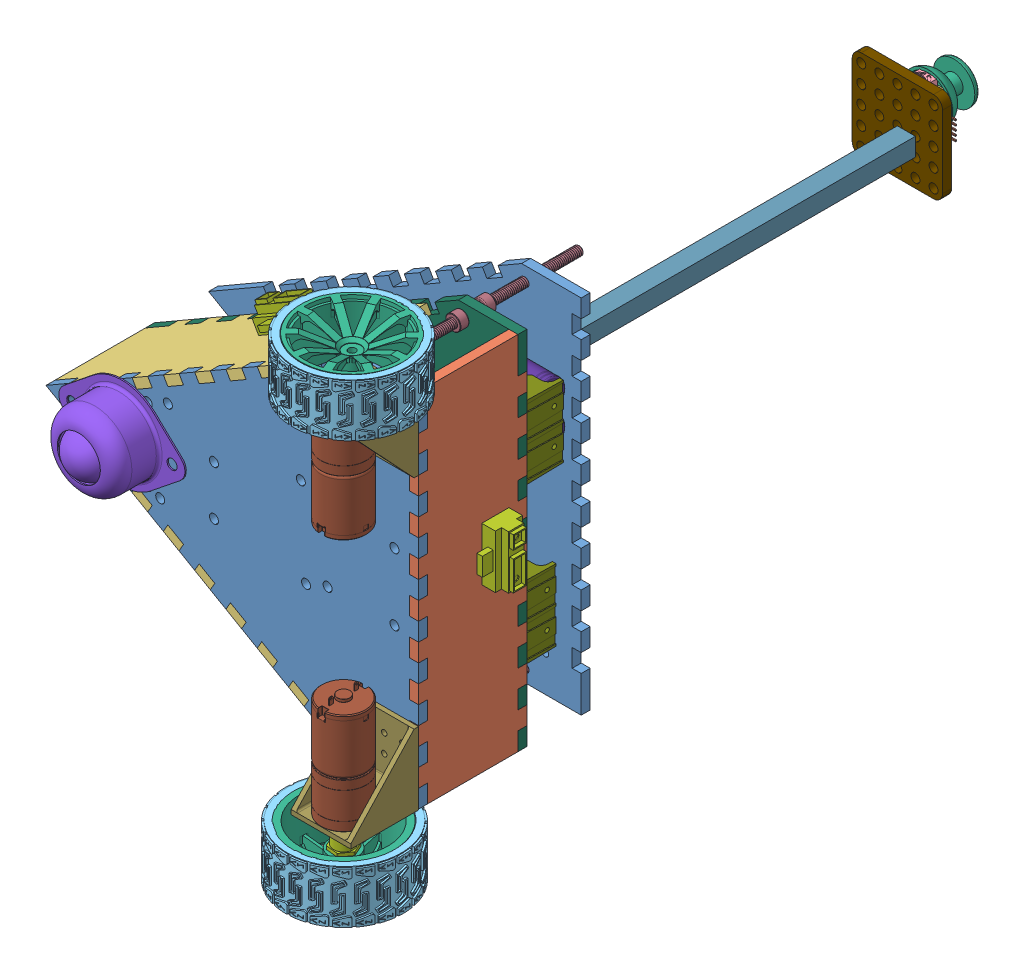
SolidWorks assembly Final_R03, configuration Default. Lengths in mm.
Overall size (224.4 260.03 452.74).
45 component instances, 25 part files, 65 mates.
Components (placement in the parent):
- triangular base 1-1: triangular base 1 [Default] at (154.8111 203.7551 170.4098) size (206.21 200 5)
- the back wall-1: the back wall [Default] at (152.3111 203.7551 170.4098) x (1 0 0) z (0 1 0) size (5 60 200)
- Walls-1: Walls [Default] at (-31.5732 93.7549 170.4098) x (0.866025 -0.5 0) z (0.5 0.866025 0) size (180 60 5)
- Walls-2: Walls [Default] at (-46.394 99.4249 170.4098) x (0.866025 0.5 0) z (-0.5 0.866025 0) size (180 60 5)
- ArduinoMega2560-1: ArduinoMega2560 [Predeterminado] at (124.9198 138.7551 169.4098) x (0 1 0) z (-1 0 0) size (100 11.65 51.63)
- blue_wheel_with_adapter-1: blue_wheel_with_adapter [Default] at (122.4376 180.4937 248.1171) x (1 0 0) z (0 1 0) size (69.31 69.31 29.8)
  - 65mm tire-1: 65mm tire [Default] at (18.1044 52.2783 38.5614) x (-0.068419 0.997657 0) z (0 0 1) size (65.01 65.01 29)
  - blue_wheel_frame-2: blue_wheel_frame [Default] at (18.0756 52.6985 38.5614) x (0 0 -1) z (-0.994893 -0.10093 0) size (29 56 56)
  - motor_adapter-1: motor_adapter [Default] at (18.0661 52.7117 35.2614) x (0.583313 -0.812247 0) z (0 0 1) size (13.7 12 18.23)
- blue_wheel_with_adapter-2: blue_wheel_with_adapter [Default] at (122.7449 26.5815 147.6981) x (1 0 0) z (0 -1 0) size (69.31 69.31 29.8)
  - 65mm tire-1: 65mm tire [Default] at (18.1044 52.2783 38.5614) x (-0.068419 0.997657 0) z (0 0 1) size (65.01 65.01 29)
  - blue_wheel_frame-2: blue_wheel_frame [Default] at (18.0756 52.6985 38.5614) x (0 0 -1) z (-0.994893 -0.10093 0) size (29 56 56)
  - motor_adapter-1: motor_adapter [Default] at (18.0661 52.7117 35.2614) x (0.583313 -0.812247 0) z (0 0 1) size (13.7 12 18.23)
- Flange-Mount Ball Transfer-1: Flange-Mount Ball Transfer [Default] at (-6.1349 102.6468 176.1718) x (0.039893 0.999204 0) z (-0.999204 0.039893 0) size (50.8 30.16 69.85)
- l298n1-1: l298n1 [Default] at (23.2111 102.2551 170.4098) x (0 -1 0) z (0 0 -1) size (43 43 26.5)
- MiniBreadboard-1: MiniBreadboard [Default] at (129.5111 61.4551 170.4098) x (0 1 0) z (-1 0 0) size (34.6 8.15 45.6)
- JGA25-372 24V Motor-1: JGA25-372 24V Motor [Ratio 171 & 226] at (140.8111 5.8202 200.4098) x (0 0 -1) z (-1 0 0) size (25.02 71.1 25)
- JGA25-372 24V Motor-2: JGA25-372 24V Motor [Ratio 171 & 226] at (140.8111 201.2551 200.4098) x (0 0 1) z (-1 0 0) size (25.02 71.1 25)
- L HOLDER DC MOTOR-1: L HOLDER DC MOTOR [Default] at (126.8111 203.7551 175.4098) x (1 0 0) z (0 -1 0) size (33 37.5 40)
- L HOLDER DC MOTOR-2: L HOLDER DC MOTOR [Default] at (154.8111 3.3202 175.4098) x (-1 0 0) z (0 1 0) size (33 37.5 40)
- M5 x 50mm CAPHEAD BOLT-1: M5 x 50mm CAPHEAD BOLT [Default] at (126.3207 196.2551 125.4098) x (1 0 0) z (0 1 0) size (8.4 55.33 8.4)
- M5 x 50mm CAPHEAD BOLT-2: M5 x 50mm CAPHEAD BOLT [Default] at (126.3207 11.2551 125.4098) x (0.989821 -0.142315 0) z (0.142315 0.989821 0) size (8.4 55.33 8.4)
- IV Stand-1: IV Stand [Default] at (72.3111 103.7551 -179.5902) x (1 0 0) z (0 -1 0) size (10 350 10)
- 1st Layer-1: 1st Layer [Default] at (154.8111 203.7551 115.4098) size (206.21 200 5)
- Batt_Pack_Main-1: Batt_Pack_Main [Défaut] at (154.2111 148.5592 115.4098) x (0 1 0) z (-1 0 0) size (40.4 21.36 77.92)
- Batt_Pack_Main-2: Batt_Pack_Main [Défaut] at (76.4911 58.5407 115.4102) x (0 -1 0) z (1 0 0) size (40.4 21.36 77.92)
- Batt_main-1: Batt_main [Défaut] at (84.3111 68.6601 104.2466) x (0 -1 0) z (0 0 1) size (18.2 64.88 18.2)
- Batt_main-2: Batt_main [Défaut] at (85.3311 157.6592 96.0342) x (0 -0.990599 -0.136795) z (0 -0.136795 0.990599) size (18.2 64.88 18.2)
- Batt_main-5: Batt_main [Défaut] at (85.3311 139.4592 96.0342) x (0 0.990599 -0.136795) z (0 -0.136795 -0.990599) size (18.2 64.88 18.2)
- Batt_main-6: Batt_main [Défaut] at (84.3111 48.4213 104.2466) x (0 1 0) z (0 0 -1) size (18.2 64.88 18.2)
- M5 x 50mm CAPHEAD BOLT-4: M5 x 50mm CAPHEAD BOLT [Default] at (126.3207 11.2551 105.4098) x (0.989821 -0.142315 0) z (-0.142315 -0.989821 0) size (8.4 55.33 8.4)
- M5 x 50mm CAPHEAD BOLT-5: M5 x 50mm CAPHEAD BOLT [Default] at (126.3207 196.2551 105.4098) x (1 0 0) z (0 -1 0) size (8.4 55.33 8.4)
- Addational useful layer 2-1: Addational useful layer 2 [Default] at (67.3111 108.7551 -179.5902) x (1 0 0) z (0 1 0) size (50 5 50)
- Top layer-1: Top layer [Default] at (154.8111 3.7551 85.4098) x (1 0 0) z (0 0 -1) size (206.21 200 5)
- Joystick assembly-1: Joystick assembly [Default] at (82.3111 123.7551 -186.0902) x (0 -1 0) z (1 0 0) size (30.12 34.52 39.55)
  - board-1: board [Default] at origin size (26.4 6.02 39.55)
  - Thumb Joystick-1: Thumb Joystick [기본] at (15.2543 37 -18.0537) x (1 0 0) z (0 -1 0) size (30.12 30.12 34.52)
    - body-1: body [기본] at (-10.9543 -7.0963 23.5) size (22.1 16 23.5)
    - potentiometer-1: potentiometer [기본] at (-2.9543 -7.0963 29) x (-1 0 0) z (0 -1 0) size (9.5 14.5 3.5)
    - potentiometer-2: potentiometer [기본] at (-10.9543 0.9037 29.5) x (0 1 0) z (-1 0 0) size (9.5 14.5 3.5)
    - tactileswitch-short-1: tactileswitch-short [Default] at (7.6493 0.9037 34) x (0 -1 0) z (1 0 0) size (6.89 8.33 6.01)
    - joystickhead-1: joystickhead [기본] at (-21.7711 -52.5336 38.75) x (0.118335 0.992974 0) z (0 0 -1) size (27.11 27.11 19.35)
- sharp 2y0a21 f 21-4: sharp 2y0a21 f 21 [Standard] at (157.3111 123.2551 140.4098) x (0 -1 0) z (0 0 1) size (29.5 13.5 21)
- sharp 2y0a21 f 21-5: sharp 2y0a21 f 21 [Standard] at (33.8114 151.5051 140.4098) x (0.866025 0.5 0) z (0 0 1) size (29.5 13.5 21)
- sharp 2y0a21 f 21-6: sharp 2y0a21 f 21 [Standard] at (59.6596 41.0816 140.4098) x (-0.866025 0.5 0) z (0 0 1) size (29.5 13.5 21)
Mates (geometry in assembly coordinates):
- Coincident3: coincident anti-aligned: plane of triangular base 1-1 through (154.8111 203.7551 175.4098) normal (0 0 1); plane of L HOLDER DC MOTOR-2 through (126.8111 43.3202 175.4098) normal (0 0 -1)
- Coincident5: coincident anti-aligned: plane of triangular base 1-1 through (154.8111 203.7551 175.4098) normal (0 0 1); plane of L HOLDER DC MOTOR-1 through (154.8111 163.7551 175.4098) normal (0 0 -1)
- Concentric6: concentric aligned: cylinder of JGA25-372 24V Motor-2 through (149.3111 201.2551 200.4098) axis (0 1 0) radius 1.25; cylinder of L HOLDER DC MOTOR-1 through (149.3111 163.7551 200.4098) axis (0 1 0) radius 1.5
- Concentric7: concentric anti-aligned: cylinder of JGA25-372 24V Motor-2 through (140.8111 218.4119 200.4098) axis (0 -1 0) radius 2; cylinder of L HOLDER DC MOTOR-1 through (140.8111 163.7551 200.4098) axis (0 1 0) radius 3.75
- Coincident7: coincident anti-aligned: plane of JGA25-372 24V Motor-1 through (140.8111 5.8202 200.4098) normal (0 -1 0); plane of L HOLDER DC MOTOR-2 through (126.8111 5.8202 212.9098) normal (0 1 0)
- Concentric8: concentric aligned: cylinder of JGA25-372 24V Motor-1 through (149.3111 5.8202 200.4098) axis (0 -1 0) radius 1.25; cylinder of L HOLDER DC MOTOR-2 through (149.3111 43.3202 200.4098) axis (0 -1 0) radius 1.5
- Concentric9: concentric aligned: cylinder of JGA25-372 24V Motor-1 through (132.3111 5.8202 200.4098) axis (0 -1 0) radius 1.25; cylinder of L HOLDER DC MOTOR-2 through (132.3111 43.3202 200.4098) axis (0 -1 0) radius 1.5
- Concentric13: concentric aligned: cylinder of triangular base 1-1 through (-33.894 103.7551 170.4098) axis (0 0 1) radius 2.5; cylinder of Flange-Mount Ball Transfer-1 through (-33.894 103.7551 175.4098) axis (0 0 1) radius 2.7781
- Coincident11: coincident anti-aligned: plane of triangular base 1-1 through (154.8111 203.7551 175.4098) normal (0 0 1); plane of Flange-Mount Ball Transfer-1 through (-6.1349 102.6468 175.4098) normal (0 0 -1)
- Coincident13: coincident aligned: line of triangular base 1-1 through (-48.894 103.7551 170.4098) axis (0.866025 0.5 0); line of Walls-2 through (-48.894 103.7551 170.4098) axis (0.866025 0.5 0)
- Coincident14: coincident aligned: line of triangular base 1-1 through (-48.894 103.7551 175.4098) axis (0 0 -1); line of Walls-2 through (-48.894 103.7551 170.4098) axis (0 0 -1)
- Coincident19: coincident aligned: line of triangular base 1-1 through (157.3111 203.7551 170.4098) axis (-1 0 0); line of the back wall-1 through (157.3111 203.7551 170.4098) axis (-1 0 0)
- Coincident20: coincident: moEndPointRef_w of triangular base 1-1; line of the back wall-1 through (157.3111 203.7551 120.4098) axis (0 0 1)
- Coincident26: coincident anti-aligned: plane of the back wall-1 through (152.3111 203.7551 170.4098) normal (-1 0 0); plane of MiniBreadboard-1 through (152.3111 44.1551 162.2598) normal (1 0 0)
- Coincident27: coincident aligned: plane of triangular base 1-1 through (154.8111 203.7551 175.4098) normal (0 1 0); plane of L HOLDER DC MOTOR-1 through (154.8111 203.7551 175.4098) normal (0 1 0)
- Concentric16: concentric anti-aligned: cylinder of blue_wheel_with_adapter-2/motor_adapter-1 through (140.8111 3.3202 200.4098) axis (0 -1 0) radius 5.5; cylinder of JGA25-372 24V Motor-1 through (140.8111 -11.3367 200.4098) axis (0 1 0) radius 2
- Coincident30: coincident anti-aligned: plane of blue_wheel_with_adapter-2/motor_adapter-1 through (140.8111 3.3202 200.4098) normal (0 1 0); plane of L HOLDER DC MOTOR-2 through (126.8111 3.3202 175.4098) normal (0 -1 0)
- Distance19: distance = 2 mm aligned: plane of ArduinoMega2560-1 through (124.9198 138.7551 168.4098) normal (0 0 -1); plane of triangular base 1-1 through (154.8111 203.7551 170.4098) normal (0 0 -1)
- Distance20: distance = 15 mm aligned: plane of ArduinoMega2560-1 through (98.4198 188.7551 168.4098) normal (0 1 0); plane of triangular base 1-1 through (154.8111 203.7551 175.4098) normal (0 1 0)
- Distance21: distance = 2 mm anti-aligned: plane of ArduinoMega2560-1 through (150.3111 188.7551 178.4098) normal (1 0 0); plane of the back wall-1 through (152.3111 203.7551 170.4098) normal (-1 0 0)
- Distance22: distance = 0 mm anti-aligned: plane of MiniBreadboard-1 through (106.7111 78.7551 170.4098) normal (0 0 1); plane of triangular base 1-1 through (154.8111 203.7551 170.4098) normal (0 0 -1)
- Distance23: distance = 10 mm anti-aligned: plane of MiniBreadboard-1 through (152.3111 78.7551 162.2598) normal (0 1 0); plane of ArduinoMega2560-1 through (98.4198 88.7551 168.4098) normal (0 -1 0)
- Coincident47: coincident aligned: plane of triangular base 1-1 through (154.8111 203.7551 170.4098) normal (0 0 -1); plane of l298n1-1 through (23.2111 102.2551 170.4098) normal (0 0 -1)
- Distance26: distance = 105 mm anti-aligned: plane of l298n1-1 through (1.7111 80.7551 170.4098) normal (1 0 0); plane of MiniBreadboard-1 through (106.7111 44.1551 162.2598) normal (-1 0 0)
- Distance27: distance = 80 mm anti-aligned: plane of triangular base 1-1 through (154.8111 203.7551 175.4098) normal (0 1 0); plane of l298n1-1 through (1.7111 123.7551 170.4098) normal (0 -1 0)
- Distance28: distance = 0 mm aligned: plane of Walls-1 through (-29.0732 98.085 175.4098) normal (0 0 1); plane of triangular base 1-1 through (154.8111 203.7551 175.4098) normal (0 0 1)
- Distance29: distance = -2000 mm anti-aligned: plane of triangular base 1-1 through (27.2181 65.5852 170.4098) normal (-0.5 -0.866025 0); plane of Walls-1 through (-29.0732 98.085 170.4098) normal (0.5 0.866025 0)
- Concentric18: concentric aligned: cylinder of triangular base 1-1 through (126.3207 196.2551 170.4098) axis (0 0 1) radius 2.5; cylinder of M5 x 50mm CAPHEAD BOLT-1 through (126.3207 196.2551 120.4098) axis (0 0 1) radius 4.2
- Coincident54: coincident aligned: plane of triangular base 1-1 through (157.3111 203.7551 175.4098) normal (1 0 0); plane of L HOLDER DC MOTOR-1 through (157.3111 203.7551 175.4098) normal (1 0 0)
- Distance36: distance = 0 mm: cylinder of blue_wheel_with_adapter-1/motor_adapter-1 through (140.5132 215.7551 195.4186) axis (0 -1 0) radius 3; cylinder of JGA25-372 24V Motor-2 through (140.8111 218.4119 200.4098) axis (0 -1 0) radius 2
- Distance37: distance = 0 mm anti-aligned: plane of blue_wheel_with_adapter-1/motor_adapter-1 through (140.5038 203.7551 195.4054) normal (0 -1 0); plane of L HOLDER DC MOTOR-1 through (154.8111 203.7551 175.4098) normal (0 1 0)
- Distance42: distance = 50 mm aligned: plane of M5 x 50mm CAPHEAD BOLT-2 through (126.3207 11.2551 120.4098) normal (0 0 -1); plane of triangular base 1-1 through (154.8111 203.7551 170.4098) normal (0 0 -1)
- Concentric23: concentric anti-aligned: circle of triangular base 1-1; circle of M5 x 50mm CAPHEAD BOLT-2
- Distance44: distance = 0 mm anti-aligned: plane of IV Stand-1 through (72.3111 103.7551 170.4098) normal (0 0 1); plane of triangular base 1-1 through (154.8111 203.7551 170.4098) normal (0 0 -1)
- Distance45: distance = 80 mm aligned: plane of IV Stand-1 through (77.3111 108.7551 170.4098) normal (1 0 0); plane of the back wall-1 through (157.3111 203.7551 170.4098) normal (1 0 0)
- Distance46: distance = 95 mm aligned: plane of IV Stand-1 through (67.3111 108.7551 170.4098) normal (0 1 0); plane of the back wall-1 through (157.3111 203.7551 170.4098) normal (0 1 0)
- Coincident71: coincident aligned: plane of the back wall-1 through (157.3111 203.7551 170.4098) normal (1 0 0); plane of 1st Layer-1 through (157.3111 203.7551 120.4098) normal (1 0 0)
- Distance56: distance = 0 mm aligned: plane of 1st Layer-1 through (154.8111 3.7551 120.4098) normal (0 -1 0); plane of triangular base 1-1 through (154.8111 3.7551 175.4098) normal (0 -1 0)
- Coincident74: coincident anti-aligned: plane of the back wall-1 through (157.3111 203.7551 120.4098) normal (0 0 -1); plane of 1st Layer-1 through (154.8111 203.7551 120.4098) normal (0 0 1)
- Distance62: distance = 1 mm aligned: plane of Batt_Pack_Main-1 through (156.3111 148.5592 115.4098) normal (1 0 0); plane of the back wall-1 through (157.3111 203.7551 170.4098) normal (1 0 0)
- Distance70: distance = 90 mm aligned: plane of Batt_Pack_Main-2 through (150.2111 78.7324 115.0009) normal (0 0.999795 -0.020266); plane of Batt_Pack_Main-1 through (80.4911 168.7509 115.0005) normal (0 0.999795 -0.020266)
- Distance71: distance = 5 mm aligned: plane of Batt_Pack_Main-2 through (152.3111 58.5407 115.4102) normal (1 0 0); plane of the back wall-1 through (157.3111 203.7551 170.4098) normal (1 0 0)
- Tangent3: tangent anti-aligned: plane of Batt_Pack_Main-1; cylinder of Batt_main-2 through (85.3311 157.6592 96.0342) axis (-1 0 0) radius 9.1
- Coincident95: coincident anti-aligned: plane of Batt_Pack_Main-1 through (150.2111 148.5592 98.6698) normal (-1 0 0); plane of Batt_main-2 through (150.2111 157.6592 96.0342) normal (1 0 0)
- Coincident96: coincident anti-aligned: plane of Batt_Pack_Main-1 through (84.4911 148.5592 98.6698) normal (1 0 0); plane of Batt_main-1 through (84.4911 61.6601 104.2466) normal (-1 0 0)
- Parallel19: parallel aligned: cylinder of Batt_main-1 through (84.3111 68.6601 104.2466) axis (-1 0 0) radius 9.1; cylinder of Batt_main-2 through (85.3311 157.6592 96.0342) axis (-1 0 0) radius 9.1
- Parallel21: parallel anti-aligned: plane of Batt_Pack_Main-2 through (146.2111 58.5407 98.6702) normal (-1 0 0); plane of Batt_main-1 through (149.1911 68.6601 104.2466) normal (1 0 0)
- Coincident97: coincident anti-aligned: plane of IV Stand-1 through (72.3111 103.7551 -179.5902) normal (0 0 -1); plane of Addational useful layer 2-1 through (87.3111 88.7551 -179.5902) normal (0 0 1)
- Distance73: distance = 25 mm aligned: plane of IV Stand-1 through (67.3111 108.7551 170.4098) normal (0 1 0); plane of Addational useful layer 2-1 through (87.3111 133.7551 -184.5902) normal (0 1 0)
- Distance72: distance = 25 mm aligned: plane of Addational useful layer 2-1 through (42.3111 128.7551 -184.5902) normal (-1 0 0); plane of IV Stand-1 through (67.3111 108.7551 170.4098) normal (-1 0 0)
- Coincident101: coincident aligned: plane of 1st Layer-1 through (154.8111 203.7551 120.4098) normal (0 1 0); plane of Top layer-1 through (154.8111 203.7551 80.4098) normal (0 1 0)
- Coincident103: coincident aligned: plane of the back wall-1 through (157.3111 203.7551 170.4098) normal (1 0 0); plane of Top layer-1 through (157.3111 3.7551 80.4098) normal (1 0 0)
- Distance74: distance = 35 mm aligned: plane of Top layer-1 through (154.8111 3.7551 80.4098) normal (0 0 -1); plane of 1st Layer-1 through (154.8111 203.7551 115.4098) normal (0 0 -1)
- Distance77: distance = 3 mm: plane of Addational useful layer 2-1 through (87.3111 88.7551 -184.5902) normal (0 0 -1); line of Joystick assembly-1/Thumb Joystick-1/body-1 through (73.1611 105.1551 -187.5902) axis (0 1 0)
- Distance82: distance = 10 mm aligned: plane of Addational useful layer 2-1 through (92.3111 128.7551 -184.5902) normal (1 0 0); plane of Joystick assembly-1/board-1 through (82.3111 123.7551 -187.5902) normal (1 0 0)
- Distance83: distance = 10 mm aligned: plane of Joystick assembly-1/board-1 through (82.3111 123.7551 -187.5902) normal (0 1 0); plane of Addational useful layer 2-1 through (87.3111 133.7551 -184.5902) normal (0 1 0)
- Coincident118: coincident anti-aligned: plane of Walls-2 through (-48.894 103.7551 170.4098) normal (-0.5 0.866025 0); plane of sharp 2y0a21 f 21-5 through (33.8114 151.5051 125.4098) normal (0.5 -0.866025 0)
- Distance84: distance = 55 mm aligned: plane of Walls-2 through (106.9905 193.7551 170.4098) normal (0.866025 0.5 0); plane of sharp 2y0a21 f 21-5 through (55.6091 172.7503 140.4098) normal (0.866025 0.5 0)
- Distance85: distance = 10 mm aligned: plane of 1st Layer-1 through (154.8111 203.7551 115.4098) normal (0 0 -1); plane of sharp 2y0a21 f 21-5 through (30.0614 158.0003 125.4098) normal (0 0 -1)
- Coincident121: coincident anti-aligned: plane of Walls-1 through (-31.5732 93.7549 170.4098) normal (-0.5 -0.866025 0); plane of sharp 2y0a21 f 21-6 through (59.6596 41.0816 125.4098) normal (0.5 0.866025 0)
- Distance88: distance = 10 mm aligned: plane of sharp 2y0a21 f 21-6 through (55.9096 34.5864 125.4098) normal (0 0 -1); plane of 1st Layer-1 through (154.8111 203.7551 115.4098) normal (0 0 -1)
- Coincident126: coincident anti-aligned: plane of the back wall-1 through (157.3111 203.7551 170.4098) normal (1 0 0); plane of sharp 2y0a21 f 21-4 through (157.3111 123.2551 125.4098) normal (-1 0 0)
- Distance89: distance = 10 mm aligned: plane of sharp 2y0a21 f 21-4 through (164.8111 123.2551 125.4098) normal (0 0 -1); plane of 1st Layer-1 through (154.8111 203.7551 115.4098) normal (0 0 -1)
- Distance90: distance = 90 mm aligned: plane of the back wall-1 through (157.3111 3.7551 170.4098) normal (0 -1 0); plane of sharp 2y0a21 f 21-4 through (164.8111 93.7551 140.4098) normal (0 -1 0)
- Distance94: distance = 0 mm anti-aligned: plane of Batt_Pack_Main-1 through (80.4911 148.5592 115.4098) normal (0 0 1); plane of 1st Layer-1 through (154.8111 203.7551 115.4098) normal (0 0 -1)
